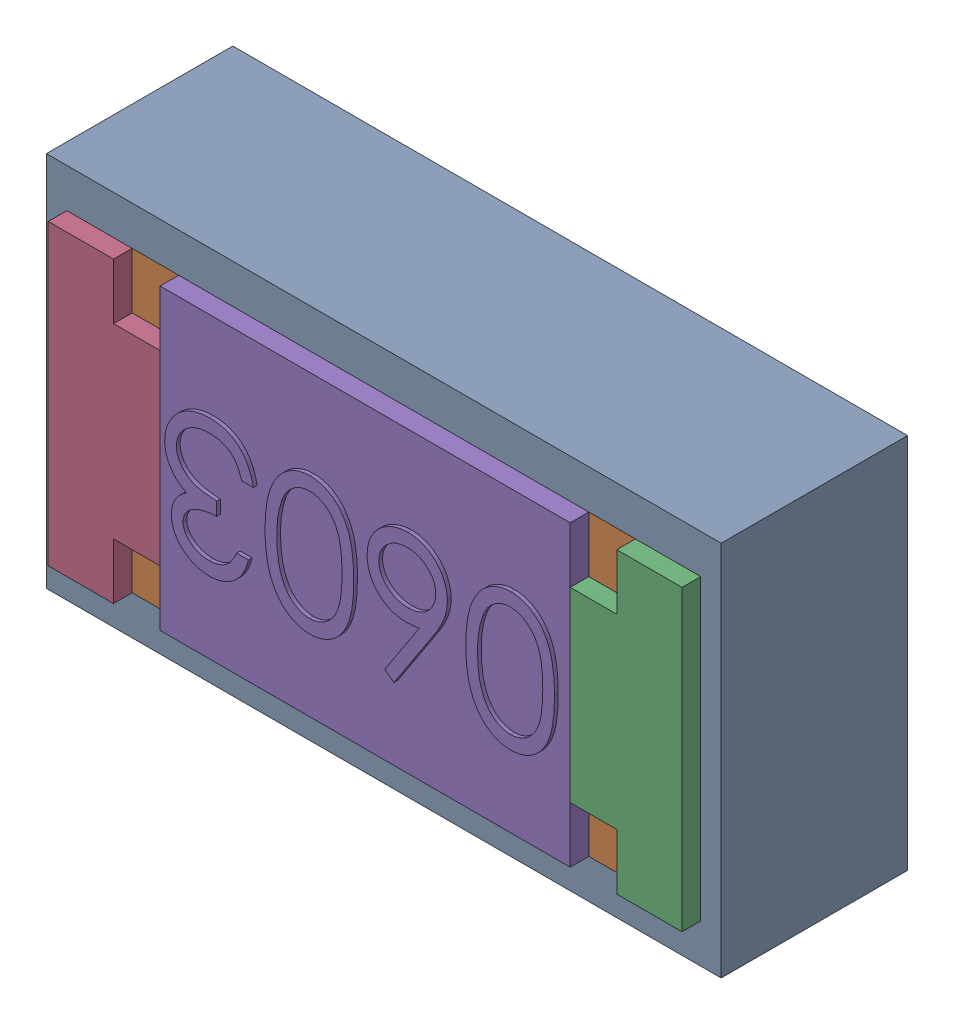
SolidWorks assembly SB2, configuration Default. Lengths in mm.
Overall size (1.81 1.01 0.56).
3 component instances, 2 part files, 0 mates.
Components (placement in the parent):
- 1088884160-1: 1088884160 [Default] at (8.175 26.175 0) size (1.81 1.01 0.5)
  - Extruded-27-1: Extruded-27 [Default] at origin size (1.81 1.01 0.5)
- R0603-1: R0603 [Default] at (8.1749 26.1749 0) x (-1 0 0) z (0 1 0) size (1.7 0.56 0.8)
